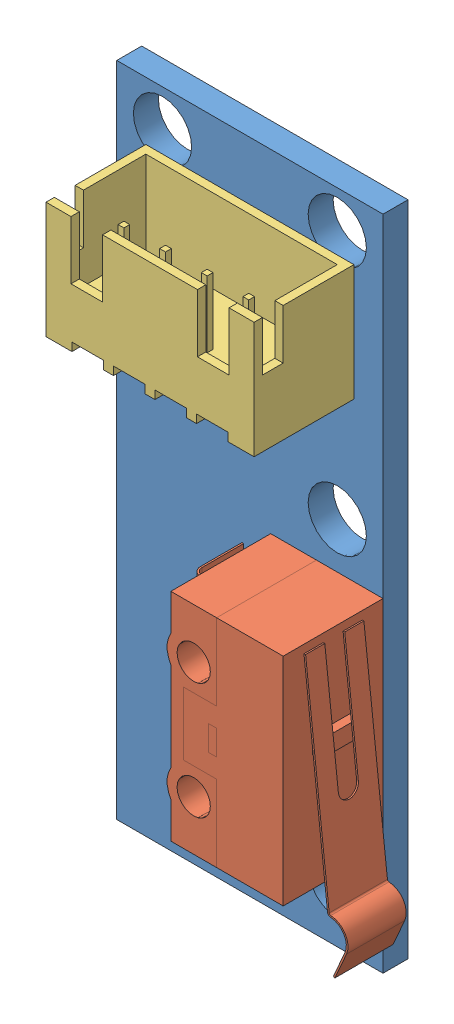
SolidWorks assembly Endstop_Microswitch_1A125VAC_DesjgnByMakerbot, configuration Défaut. Lengths in mm.
Overall size (18.65 39.5 8).
3 component instances, 3 part files, 7 mates.
Components (placement in the parent):
- PCB^Endstop_Microswitch_1A125VAC_DesjgnByMakerbot-1: PCB^Endstop_Microswitch_1A125VAC_DesjgnByMakerbot [Défaut] at origin size (16 39.5 1.5) (virtual)
- Microswitch_1A_125vAC(seul)-1: Microswitch_1A_125vAC(seul) [Défaut] at (0 -6.75 4.5) size (11.12 16.44 8)
- Connecteur^Endstop_Microswitch_1A125VAC_DesjgnByMakerbot-1: Connecteur^Endstop_Microswitch_1A125VAC_DesjgnByMakerbot [Défaut] at (0 0 1.5) size (12.5 7.35 8) (virtual)
Mates (geometry in assembly coordinates):
- Coïncidente4: coincident anti-aligned: plane of PCB^Endstop_Microswitch_1A125VAC_DesjgnByMakerbot-1 through (0 0 1.5) normal (0 0 1); plane of Microswitch_1A_125vAC(seul)-1 through (0 -6.75 1.5) normal (0 0 -1)
- Distance1: distance = 6.5 mm aligned: plane of Microswitch_1A_125vAC(seul)-1 through (-4 -13.25 7.5) normal (0 -1 0); plane of PCB^Endstop_Microswitch_1A125VAC_DesjgnByMakerbot-1 through (-16 -19.75 1.5) normal (0 -1 0)
- Coïncidente7: coincident aligned: plane of PCB^Endstop_Microswitch_1A125VAC_DesjgnByMakerbot-1 through (0 19.75 1.5) normal (1 0 0); plane of Microswitch_1A_125vAC(seul)-1 through (0 -0.25 7.5) normal (1 0 0)
- Sur place2: in place: plane of PCB^Endstop_Microswitch_1A125VAC_DesjgnByMakerbot-1 through (0 0 1.5) normal (0 0 1); plane of Connecteur^Endstop_Microswitch_1A125VAC_DesjgnByMakerbot-1 through (0 0 1.5) normal (0 0 1); moOrthogonalPlaneRef_w of PCB^Endstop_Microswitch_1A125VAC_DesjgnByMakerbot-1 through (0 0 1.5) normal (0 0 1); plane of Connecteur^Endstop_Microswitch_1A125VAC_DesjgnByMakerbot-1 through (0 0 1.5) normal (0 1 0); plane of PCB^Endstop_Microswitch_1A125VAC_DesjgnByMakerbot-1 through (0 0 1.5) normal (0 0 1); plane of Connecteur^Endstop_Microswitch_1A125VAC_DesjgnByMakerbot-1 through (0 0 1.5) normal (1 0 0); plane of PCB^Endstop_Microswitch_1A125VAC_DesjgnByMakerbot-1 through (0 0 1.5) normal (0 0 1); unknown of Connecteur^Endstop_Microswitch_1A125VAC_DesjgnByMakerbot-1
- Coïncidente8: coincident aligned: plane of PCB^Endstop_Microswitch_1A125VAC_DesjgnByMakerbot-1; plane of Connecteur^Endstop_Microswitch_1A125VAC_DesjgnByMakerbot-1
- Coïncidente9: coincident aligned: moOrthogonalPlaneRef_w of PCB^Endstop_Microswitch_1A125VAC_DesjgnByMakerbot-1 through (0 0 1.5) normal (0 1 0); plane of Connecteur^Endstop_Microswitch_1A125VAC_DesjgnByMakerbot-1 through (0 0 1.5) normal (0 1 0)
- Coïncidente10: coincident anti-aligned: moOrthogonalPlaneRef_w of PCB^Endstop_Microswitch_1A125VAC_DesjgnByMakerbot-1 through (0 0 1.5) normal (-1 0 0); plane of Connecteur^Endstop_Microswitch_1A125VAC_DesjgnByMakerbot-1 through (0 0 1.5) normal (1 0 0)
